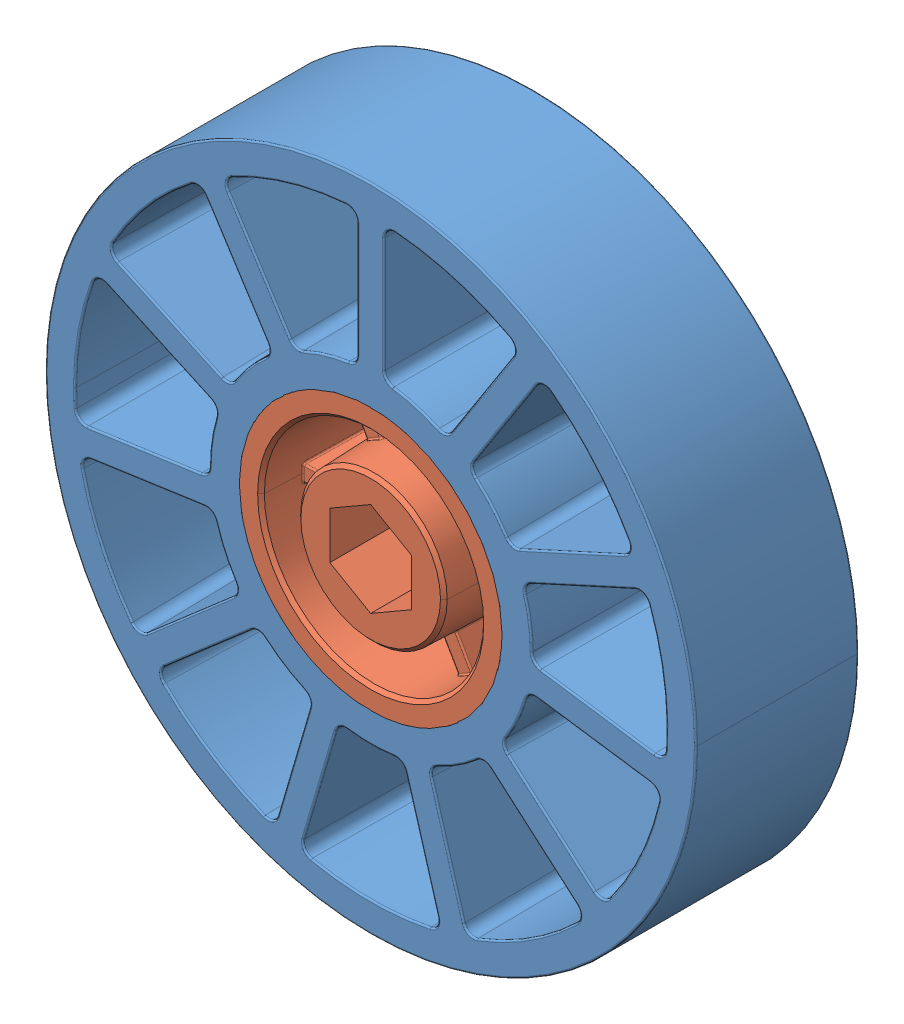
SolidWorks assembly am-3480 4IN 500Hex Compliant Wheel REV2, configuration Default. Lengths in mm.
Overall size (101.6 101.6 25.4).
3 component instances, 2 part files, 0 mates.
Components (placement in the parent):
- am-3480 4IN 500Hex Compliant Wheel REV2.STEP-1: am-3480 4IN 500Hex Compliant Wheel REV2.STEP [Default] at origin size (101.6 101.6 25.4)
  - 4IN Compliant Wheel FINAL Overmold.STEP-1: 4IN Compliant Wheel FINAL Overmold.STEP [Default] at (-16.2374 3.8509 18.652) size (101.6 101.6 25.4)
  - 2in Wheel Intergrated 0500 HEX Hub.STEP-1: 2in Wheel Intergrated 0500 HEX Hub.STEP [Default] at (-16.2374 3.8509 5.952) x (-1 0 0) z (0 0 -1) size (41.91 41.91 25.4)
